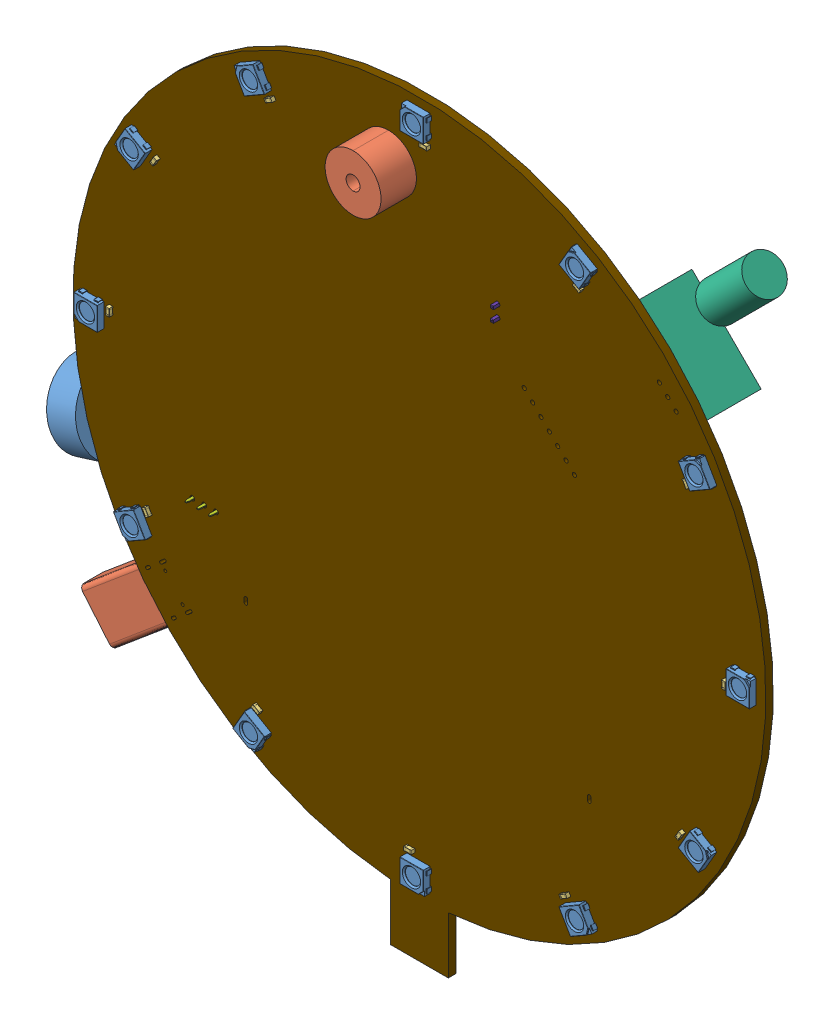
SolidWorks assembly Semafor2_kompletni, configuration Výchozí. Lengths in mm.
Overall size (154.19 160.68 28.8).
173 component instances, 20 part files, 6 mates.
Components (placement in the parent):
- Semafor2-1: Semafor2 [Výchozí] at origin size (148.79 160.68 28.8)
  - Semafor2.step-1: Semafor2.step [Výchozí] at origin size (148.79 160.68 28.8)
    - LED_WS2812B_PLCC4_5.0x5.0mm_P3.2mm.step-1: LED_WS2812B_PLCC4_5.0x5.0mm_P3.2mm.step [Výchozí] at (-39.4282 65.1 1.65) x (0.5 0.866025 0) z (0 0 1) size (5.4 5 1.6)
      - SOLID.step-1: SOLID.step [Výchozí] at origin size (5.4 5 1.6)
    - Piezo.step-1: Piezo.step [Výchozí] at (-106.6 158.895 1.65) x (1 0 0) z (0 -1 0) size (12 7.6 12)
      - SOLID-0.step-1: SOLID-0.step [Výchozí] at origin size (12 7.6 12)
    - LED_WS2812B_PLCC4_5.0x5.0mm_P3.2mm.step-2: LED_WS2812B_PLCC4_5.0x5.0mm_P3.2mm.step [Výchozí] at (-30.05 100.1 1.65) x (0 1 0) z (0 0 1) size (5.4 5 1.6)
      - SOLID.step-1: SOLID.step [Výchozí] at origin size (5.4 5 1.6)
    - LED_WS2812B_PLCC4_5.0x5.0mm_P3.2mm.step-3: LED_WS2812B_PLCC4_5.0x5.0mm_P3.2mm.step [Výchozí] at (-170.05 100.1 1.65) x (0 -1 0) z (0 0 1) size (5.4 5 1.6)
      - SOLID.step-1: SOLID.step [Výchozí] at origin size (5.4 5 1.6)
    - C_0603_1608Metric.step-1: C_0603_1608Metric.step [Výchozí] at (-101.75 33.8 1.65) size (1.6 0.8 0.8)
      - SOLID-1.step-1: SOLID-1.step [Výchozí] at origin size (1.6 0.8 0.8)
    - C_0603_1608Metric.step-2: C_0603_1608Metric.step [Výchozí] at (-43.5875 65.6288 1.65) x (0.5 0.866025 0) z (0 0 1) size (1.6 0.8 0.8)
      - SOLID-1.step-1: SOLID-1.step [Výchozí] at origin size (1.6 0.8 0.8)
    - C_0603_1608Metric.step-3: C_0603_1608Metric.step [Výchozí] at (-134.4288 43.6125 1.65) x (0.866025 -0.5 0) z (0 0 1) size (1.6 0.8 0.8)
      - SOLID-1.step-1: SOLID-1.step [Výchozí] at origin size (1.6 0.8 0.8)
    - C_0603_1608Metric.step-4: C_0603_1608Metric.step [Výchozí] at (-166.15 101.75 1.65) x (0 -1 0) z (0 0 1) size (1.6 0.8 0.8)
      - SOLID-1.step-1: SOLID-1.step [Výchozí] at origin size (1.6 0.8 0.8)
    - LED_WS2812B_PLCC4_5.0x5.0mm_P3.2mm.step-4: LED_WS2812B_PLCC4_5.0x5.0mm_P3.2mm.step [Výchozí] at (-100.05 30.1 1.65) size (5.4 5 1.6)
      - SOLID.step-1: SOLID.step [Výchozí] at origin size (5.4 5 1.6)
    - C_0603_1608Metric.step-5: C_0603_1608Metric.step [Výchozí] at (-158.05 68.5 1.65) x (0.5 -0.866025 0) z (0 0 1) size (1.6 0.8 0.8)
      - SOLID-1.step-1: SOLID-1.step [Výchozí] at origin size (1.6 0.8 0.8)
    - C_0603_1608Metric.step-6: C_0603_1608Metric.step [Výchozí] at (-68.35 41.95 1.65) x (0.866025 0.5 0) z (0 0 1) size (1.6 0.8 0.8)
      - SOLID-1.step-1: SOLID-1.step [Výchozí] at origin size (1.6 0.8 0.8)
    - LED_WS2812B_PLCC4_5.0x5.0mm_P3.2mm.step-5: LED_WS2812B_PLCC4_5.0x5.0mm_P3.2mm.step [Výchozí] at (-100.05 170.1 1.65) x (-1 0 0) z (0 0 1) size (5.4 5 1.6)
      - SOLID.step-1: SOLID.step [Výchozí] at origin size (5.4 5 1.6)
    - LED_WS2812B_PLCC4_5.0x5.0mm_P3.2mm.step-6: LED_WS2812B_PLCC4_5.0x5.0mm_P3.2mm.step [Výchozí] at (-39.4282 135.1 1.65) x (-0.5 0.866025 0) z (0 0 1) size (5.4 5 1.6)
      - SOLID.step-1: SOLID.step [Výchozí] at origin size (5.4 5 1.6)
    - LED_WS2812B_PLCC4_5.0x5.0mm_P3.2mm.step-7: LED_WS2812B_PLCC4_5.0x5.0mm_P3.2mm.step [Výchozí] at (-160.6718 65.1 1.65) x (0.5 -0.866025 0) z (0 0 1) size (5.4 5 1.6)
      - SOLID.step-1: SOLID.step [Výchozí] at origin size (5.4 5 1.6)
    - LED_WS2812B_PLCC4_5.0x5.0mm_P3.2mm.step-8: LED_WS2812B_PLCC4_5.0x5.0mm_P3.2mm.step [Výchozí] at (-65.05 39.4782 1.65) x (0.866025 0.5 0) z (0 0 1) size (5.4 5 1.6)
      - SOLID.step-1: SOLID.step [Výchozí] at origin size (5.4 5 1.6)
    - C_0603_1608Metric.step-7: C_0603_1608Metric.step [Výchozí] at (-65.45 156.55 1.65) x (-0.866025 0.5 0) z (0 0 1) size (1.6 0.8 0.8)
      - SOLID-1.step-1: SOLID-1.step [Výchozí] at origin size (1.6 0.8 0.8)
    - C_0603_1608Metric.step-8: C_0603_1608Metric.step [Výchozí] at (-33.9 98.45 1.65) x (0 1 0) z (0 0 1) size (1.6 0.8 0.8)
      - SOLID-1.step-1: SOLID-1.step [Výchozí] at origin size (1.6 0.8 0.8)
    - C_0603_1608Metric.step-9: C_0603_1608Metric.step [Výchozí] at (-98.4 166.3 1.65) x (-1 0 0) z (0 0 1) size (1.6 0.8 0.8)
      - SOLID-1.step-1: SOLID-1.step [Výchozí] at origin size (1.6 0.8 0.8)
    - LED_WS2812B_PLCC4_5.0x5.0mm_P3.2mm.step-9: LED_WS2812B_PLCC4_5.0x5.0mm_P3.2mm.step [Výchozí] at (-160.6718 135.1 1.65) x (-0.5 -0.866025 0) z (0 0 1) size (5.4 5 1.6)
      - SOLID.step-1: SOLID.step [Výchozí] at origin size (5.4 5 1.6)
    - LED_WS2812B_PLCC4_5.0x5.0mm_P3.2mm.step-10: LED_WS2812B_PLCC4_5.0x5.0mm_P3.2mm.step [Výchozí] at (-65.05 160.7218 1.65) x (-0.866025 0.5 0) z (0 0 1) size (5.4 5 1.6)
      - SOLID.step-1: SOLID.step [Výchozí] at origin size (5.4 5 1.6)
    - C_0603_1608Metric.step-10: C_0603_1608Metric.step [Výchozí] at (-156.35 134.6 1.65) x (-0.5 -0.866025 0) z (0 0 1) size (1.6 0.8 0.8)
      - SOLID-1.step-1: SOLID-1.step [Výchozí] at origin size (1.6 0.8 0.8)
    - LED_WS2812B_PLCC4_5.0x5.0mm_P3.2mm.step-11: LED_WS2812B_PLCC4_5.0x5.0mm_P3.2mm.step [Výchozí] at (-135.05 160.7218 1.65) x (-0.866025 -0.5 0) z (0 0 1) size (5.4 5 1.6)
      - SOLID.step-1: SOLID.step [Výchozí] at origin size (5.4 5 1.6)
    - C_0603_1608Metric.step-11: C_0603_1608Metric.step [Výchozí] at (-131.65 158.3 1.65) x (-0.866025 -0.5 0) z (0 0 1) size (1.6 0.8 0.8)
      - SOLID-1.step-1: SOLID-1.step [Výchozí] at origin size (1.6 0.8 0.8)
    - C_0603_1608Metric.step-12: C_0603_1608Metric.step [Výchozí] at (-42.05 131.8 1.65) x (-0.5 0.866025 0) z (0 0 1) size (1.6 0.8 0.8)
      - SOLID-1.step-1: SOLID-1.step [Výchozí] at origin size (1.6 0.8 0.8)
    - LED_WS2812B_PLCC4_5.0x5.0mm_P3.2mm.step-12: LED_WS2812B_PLCC4_5.0x5.0mm_P3.2mm.step [Výchozí] at (-135.05 39.4782 1.65) x (0.866025 -0.5 0) z (0 0 1) size (5.4 5 1.6)
      - SOLID.step-1: SOLID.step [Výchozí] at origin size (5.4 5 1.6)
    - R_0603_1608Metric.step-1: R_0603_1608Metric.step [Výchozí] at (-119.75 147.925 -0.05) x (0 -1 0) z (0 0 -1) size (1.6 0.8 0.45)
      - SOLID-2.step-1: SOLID-2.step [Výchozí] at origin size (1.6 0.8 0.45)
    - R_0603_1608Metric.step-2: R_0603_1608Metric.step [Výchozí] at (-115.95 147.9 -0.05) x (0 -1 0) z (0 0 -1) size (1.6 0.8 0.45)
      - SOLID-2.step-1: SOLID-2.step [Výchozí] at origin size (1.6 0.8 0.45)
    - D_SOD-123.step-1: D_SOD-123.step [Výchozí] at (-130.0125 82.075 -0.05) x (-1 0 0) z (0 0 -1) size (3.8 1.6 1.25)
      - SOLID-3.step-1: SOLID-3.step [Výchozí] at origin size (3.8 1.6 1.25)
    - E22_900T22D.step-1: E22_900T22D.step [Výchozí] at (-60.45 137.7711 -0.05) x (-0.707107 -0.707107 0) z (0 0 -1) size (50 21 17.3)
      - SOLID-4.step-1: SOLID-4.step [Výchozí] at origin size (50 21 17.3)
    - D_SOD-123.step-2: D_SOD-123.step [Výchozí] at (-96.1 29.05 -0.05) x (0 -1 0) z (0 0 -1) size (3.8 1.6 1.25)
      - SOLID-3.step-1: SOLID-3.step [Výchozí] at origin size (3.8 1.6 1.25)
    - PinSocket_1x03_P2.54mm_Vertical.step-1: PinSocket_1x03_P2.54mm_Vertical.step [Výchozí] at (-143.675 75.375 -0.05) x (0 1 0) z (0 0 -1) size (2.54 7.62 10.1)
      - SOLID-5.step-1: SOLID-5.step [Výchozí] at origin size (2.54 7.62 10.1)
    - D_SOD-323.step-1: D_SOD-323.step [Výchozí] at (-142.6 58.8 -0.05) x (0.642788 -0.766044 0) z (0 0 -1) size (2.5 1.25 1.1)
      - SOLID-6.step-1: SOLID-6.step [Výchozí] at origin size (2.5 1.25 1.1)
    - C_0603_1608Metric.step-13: C_0603_1608Metric.step [Výchozí] at (-158.9591 131.0993 -0.05) x (-0.939693 0.34202 0) z (0 0 -1) size (1.6 0.8 0.8)
      - SOLID-1.step-1: SOLID-1.step [Výchozí] at origin size (1.6 0.8 0.8)
    - R_0603_1608Metric.step-3: R_0603_1608Metric.step [Výchozí] at (-83.3756 132.275 -0.05) x (-1 0 0) z (0 0 -1) size (1.6 0.8 0.45)
      - SOLID-2.step-1: SOLID-2.step [Výchozí] at origin size (1.6 0.8 0.45)
    - R_0603_1608Metric.step-4: R_0603_1608Metric.step [Výchozí] at (-118.05 147.9 -0.05) x (0 -1 0) z (0 0 -1) size (1.6 0.8 0.45)
      - SOLID-2.step-1: SOLID-2.step [Výchozí] at origin size (1.6 0.8 0.45)
    - R_0603_1608Metric.step-5: R_0603_1608Metric.step [Výchozí] at (-116.95 136.3 -0.05) x (0 -1 0) z (0 0 -1) size (1.6 0.8 0.45)
      - SOLID-2.step-1: SOLID-2.step [Výchozí] at origin size (1.6 0.8 0.45)
    - C_0805_2012Metric.step-1: C_0805_2012Metric.step [Výchozí] at (-152.9591 126.5493 -0.05) x (0.939693 -0.34202 0) z (0 0 -1) size (2 1.25 1.25)
      - SOLID-7.step-1: SOLID-7.step [Výchozí] at origin size (2 1.25 1.25)
    - LED_0603_1608Metric.step-1: LED_0603_1608Metric.step [Výchozí] at (-147.525 84.025 -0.05) x (-1 0 0) z (0 0 -1) size (1.6 0.8 1.1)
      - SOLID-8.step-1: SOLID-8.step [Výchozí] at origin size (1.6 0.8 1.1)
    - SOT-23.step-1: SOT-23.step [Výchozí] at (-83.3256 136.55 -0.05) x (0 1 0) z (0 0 -1) size (2.5 3 1.2)
      - SOLID-9.step-1: SOLID-9.step [Výchozí] at origin size (2.5 3 1.2)
    - SOT-23.step-2: SOT-23.step [Výchozí] at (-146.9091 122.0993 -0.05) x (0.939693 -0.34202 0) z (0 0 -1) size (2.5 3 1.2)
      - SOLID-9.step-1: SOLID-9.step [Výchozí] at origin size (2.5 3 1.2)
    - R_0603_1608Metric.step-6: R_0603_1608Metric.step [Výchozí] at (-120.725 43.975 -0.05) x (-1 0 0) z (0 0 -1) size (1.6 0.8 0.45)
      - SOLID-2.step-1: SOLID-2.step [Výchozí] at origin size (1.6 0.8 0.45)
    - C_0805_2012Metric.step-2: C_0805_2012Metric.step [Výchozí] at (-159.7591 129.0993 -0.05) x (-0.939693 0.34202 0) z (0 0 -1) size (2 1.25 1.25)
      - SOLID-7.step-1: SOLID-7.step [Výchozí] at origin size (2 1.25 1.25)
    - R_0603_1608Metric.step-7: R_0603_1608Metric.step [Výchozí] at (-120.15 136.3 -0.05) x (0 -1 0) z (0 0 -1) size (1.6 0.8 0.45)
      - SOLID-2.step-1: SOLID-2.step [Výchozí] at origin size (1.6 0.8 0.45)
    - D_SOD-323.step-2: D_SOD-323.step [Výchozí] at (-147.5 62.875 -0.05) x (-0.766044 -0.642788 0) z (0 0 -1) size (2.5 1.25 1.1)
      - SOLID-6.step-1: SOLID-6.step [Výchozí] at origin size (2.5 1.25 1.1)
    - C_0805_2012Metric.step-3: C_0805_2012Metric.step [Výchozí] at (-128.3875 78.75 -0.05) x (0 -1 0) z (0 0 -1) size (2 1.25 1.25)
      - SOLID-7.step-1: SOLID-7.step [Výchozí] at origin size (2 1.25 1.25)
    - R_0603_1608Metric.step-8: R_0603_1608Metric.step [Výchozí] at (-143.0091 117.4493 -0.05) x (0.939693 -0.34202 0) z (0 0 -1) size (1.6 0.8 0.45)
      - SOLID-2.step-1: SOLID-2.step [Výchozí] at origin size (1.6 0.8 0.45)
    - LED_0603_1608Metric.step-2: LED_0603_1608Metric.step [Výchozí] at (-109.425 43.2125 -0.05) x (0 -1 0) z (0 0 -1) size (1.6 0.8 1.1)
      - SOLID-8.step-1: SOLID-8.step [Výchozí] at origin size (1.6 0.8 1.1)
    - R_0603_1608Metric.step-9: R_0603_1608Metric.step [Výchozí] at (-135.1875 77.025 -0.05) x (0 1 0) z (0 0 -1) size (1.6 0.8 0.45)
      - SOLID-2.step-1: SOLID-2.step [Výchozí] at origin size (1.6 0.8 0.45)
    - USB_C.step-1: USB_C.step [Výchozí] at (-154.7 55.1 -0.05) x (-0.766044 -0.642788 0) z (0 0 -1) size (7.5 9 3.5)
      - SOLID-10.step-1: SOLID-10.step [Výchozí] at origin size (7.5 9 3.5)
    - Battery_pack.step-1: Battery_pack.step [Výchozí] at (-99.9 62.1 -0.05) x (-1 0 0) z (0 0 -1) size (77 21 19.5)
      - SOLID-11.step-1: SOLID-11.step [Výchozí] at origin size (77 21 19.5)
    - LED_0603_1608Metric.step-3: LED_0603_1608Metric.step [Výchozí] at (-107.575 43.225 -0.05) x (0 -1 0) z (0 0 -1) size (1.6 0.8 1.1)
      - SOLID-8.step-1: SOLID-8.step [Výchozí] at origin size (1.6 0.8 1.1)
    - R_0603_1608Metric.step-10: R_0603_1608Metric.step [Výchozí] at (-144.1125 87.05 -0.05) x (1 0 0) z (0 0 -1) size (1.6 0.8 0.45)
      - SOLID-2.step-1: SOLID-2.step [Výchozí] at origin size (1.6 0.8 0.45)
    - D_SOD-123.step-3: D_SOD-123.step [Výchozí] at (-117.975 155.17 -0.05) x (-1 0 0) z (0 0 -1) size (3.8 1.6 1.25)
      - SOLID-3.step-1: SOLID-3.step [Výchozí] at origin size (3.8 1.6 1.25)
    - R_0603_1608Metric.step-11: R_0603_1608Metric.step [Výchozí] at (-114.175 160.345 -0.05) x (0 -1 0) z (0 0 -1) size (1.6 0.8 0.45)
      - SOLID-2.step-1: SOLID-2.step [Výchozí] at origin size (1.6 0.8 0.45)
    - R_0603_1608Metric.step-12: R_0603_1608Metric.step [Výchozí] at (-150.9091 118.3743 -0.05) x (-0.34202 -0.939693 0) z (0 0 -1) size (1.6 0.8 0.45)
      - SOLID-2.step-1: SOLID-2.step [Výchozí] at origin size (1.6 0.8 0.45)
    - D_SOD-323.step-3: D_SOD-323.step [Výchozí] at (-98.4 29.65 -0.05) x (0 1 0) z (0 0 -1) size (2.5 1.25 1.1)
      - SOLID-6.step-1: SOLID-6.step [Výchozí] at origin size (2.5 1.25 1.1)
    - SOIC-14_3.9x8.7mm_P1.27mm.step-1: SOIC-14_3.9x8.7mm_P1.27mm.step [Výchozí] at (-118.5 142.1 -0.05) x (0 -1 0) z (0 0 -1) size (6 8.7 1.75)
      - SOLID-12.step-1: SOLID-12.step [Výchozí] at origin size (6 8.7 1.75)
    - C_0603_1608Metric.step-14: C_0603_1608Metric.step [Výchozí] at (-124.55 142.3493 -0.05) x (0 -1 0) z (0 0 -1) size (1.6 0.8 0.8)
      - SOLID-1.step-1: SOLID-1.step [Výchozí] at origin size (1.6 0.8 0.8)
    - R_0603_1608Metric.step-13: R_0603_1608Metric.step [Výchozí] at (-147.4841 125.4493 -0.05) x (0.939693 -0.34202 0) z (0 0 -1) size (1.6 0.8 0.45)
      - SOLID-2.step-1: SOLID-2.step [Výchozí] at origin size (1.6 0.8 0.45)
    - C_0805_2012Metric.step-4: C_0805_2012Metric.step [Výchozí] at (-126.5 142.3993 -0.05) x (0 -1 0) z (0 0 -1) size (2 1.25 1.25)
      - SOLID-7.step-1: SOLID-7.step [Výchozí] at origin size (2 1.25 1.25)
    - R_0603_1608Metric.step-14: R_0603_1608Metric.step [Výchozí] at (-139.1625 81.2 -0.05) x (0 -1 0) z (0 0 -1) size (1.6 0.8 0.45)
      - SOLID-2.step-1: SOLID-2.step [Výchozí] at origin size (1.6 0.8 0.45)
    - R_0603_1608Metric.step-15: R_0603_1608Metric.step [Výchozí] at (-132.6875 77.875 -0.05) x (1 0 0) z (0 0 -1) size (1.6 0.8 0.45)
      - SOLID-2.step-1: SOLID-2.step [Výchozí] at origin size (1.6 0.8 0.45)
    - SOT-23.step-3: SOT-23.step [Výchozí] at (-118.675 160.445 -0.05) x (-1 0 0) z (0 0 -1) size (2.5 3 1.2)
      - SOLID-9.step-1: SOLID-9.step [Výchozí] at origin size (2.5 3 1.2)
    - R_0402_1005Metric.step-1: R_0402_1005Metric.step [Výchozí] at (-150.45 61 -0.05) x (0.766044 0.642788 0) z (0 0 -1) size (1 0.5 0.35)
      - SOLID-13.step-1: SOLID-13.step [Výchozí] at origin size (1 0.5 0.35)
    - C_0805_2012Metric.step-5: C_0805_2012Metric.step [Výchozí] at (-114.675 48.525 -0.05) x (-1 0 0) z (0 0 -1) size (2 1.25 1.25)
      - SOLID-7.step-1: SOLID-7.step [Výchozí] at origin size (2 1.25 1.25)
    - R_0603_1608Metric.step-16: R_0603_1608Metric.step [Výchozí] at (-152.1341 114.7493 -0.05) x (-0.34202 -0.939693 0) z (0 0 -1) size (1.6 0.8 0.45)
      - SOLID-2.step-1: SOLID-2.step [Výchozí] at origin size (1.6 0.8 0.45)
    - C_0603_1608Metric.step-15: C_0603_1608Metric.step [Výchozí] at (-78.4756 143.175 -0.05) x (0 -1 0) z (0 0 -1) size (1.6 0.8 0.8)
      - SOLID-1.step-1: SOLID-1.step [Výchozí] at origin size (1.6 0.8 0.8)
    - C_0805_2012Metric.step-6: C_0805_2012Metric.step [Výchozí] at (-120.625 46.525 -0.05) x (-1 0 0) z (0 0 -1) size (2 1.25 1.25)
      - SOLID-7.step-1: SOLID-7.step [Výchozí] at origin size (2 1.25 1.25)
    - R_0603_1608Metric.step-17: R_0603_1608Metric.step [Výchozí] at (-115.3 136.3 -0.05) x (0 1 0) z (0 0 -1) size (1.6 0.8 0.45)
      - SOLID-2.step-1: SOLID-2.step [Výchozí] at origin size (1.6 0.8 0.45)
    - SOT-23-5.step-1: SOT-23-5.step [Výchozí] at (-135.2875 81.1 -0.05) x (-1 0 0) z (0 0 -1) size (2.8 2.9 1.55)
      - SOLID-14.step-1: SOLID-14.step [Výchozí] at origin size (2.8 2.9 1.55)
    - R_0402_1005Metric.step-2: R_0402_1005Metric.step [Výchozí] at (-148.35 58.75 -0.05) x (0.766044 0.642788 0) z (0 0 -1) size (1 0.5 0.35)
      - SOLID-13.step-1: SOLID-13.step [Výchozí] at origin size (1 0.5 0.35)
    - C_0805_2012Metric.step-7: C_0805_2012Metric.step [Výchozí] at (-136.7875 84.075 -0.05) x (1 0 0) z (0 0 -1) size (2 1.25 1.25)
      - SOLID-7.step-1: SOLID-7.step [Výchozí] at origin size (2 1.25 1.25)
    - PinHeader_1x02_P2.54mm_Vertical.step-1: PinHeader_1x02_P2.54mm_Vertical.step [Výchozí] at (-83.2244 144.25 -0.05) x (-1 0 0) z (0 0 -1) size (2.54 5.08 11.54)
      - SOLID-15.step-1: SOLID-15.step [Výchozí] at origin size (2.54 5.08 11.54)
    - D_SOD-323.step-4: D_SOD-323.step [Výchozí] at (-146.2 61.275 -0.05) x (-0.766044 -0.642788 0) z (0 0 -1) size (2.5 1.25 1.1)
      - SOLID-6.step-1: SOLID-6.step [Výchozí] at origin size (2.5 1.25 1.1)
    - LED_0603_1608Metric.step-4: LED_0603_1608Metric.step [Výchozí] at (-147.5125 87.075 -0.05) x (-1 0 0) z (0 0 -1) size (1.6 0.8 1.1)
      - SOLID-8.step-1: SOLID-8.step [Výchozí] at origin size (1.6 0.8 1.1)
    - R_0603_1608Metric.step-18: R_0603_1608Metric.step [Výchozí] at (-156.1591 128.8493 -0.05) x (0.939693 -0.34202 0) z (0 0 -1) size (1.6 0.8 0.45)
      - SOLID-2.step-1: SOLID-2.step [Výchozí] at origin size (1.6 0.8 0.45)
    - R_0603_1608Metric.step-19: R_0603_1608Metric.step [Výchozí] at (-144.15 84.05 -0.05) x (1 0 0) z (0 0 -1) size (1.6 0.8 0.45)
      - SOLID-2.step-1: SOLID-2.step [Výchozí] at origin size (1.6 0.8 0.45)
    - R_0603_1608Metric.step-20: R_0603_1608Metric.step [Výchozí] at (-110.275 40.775 -0.05) x (1 0 0) z (0 0 -1) size (1.6 0.8 0.45)
      - SOLID-2.step-1: SOLID-2.step [Výchozí] at origin size (1.6 0.8 0.45)
    - D_SOD-123.step-4: D_SOD-123.step [Výchozí] at (-144.6 55.65 -0.05) x (-0.766044 -0.642788 0) z (0 0 -1) size (3.8 1.6 1.25)
      - SOLID-3.step-1: SOLID-3.step [Výchozí] at origin size (3.8 1.6 1.25)
    - SOT-23.step-4: SOT-23.step [Výchozí] at (-143.8591 114.7993 -0.05) x (0.939693 -0.34202 0) z (0 0 -1) size (2.5 3 1.2)
      - SOLID-9.step-1: SOLID-9.step [Výchozí] at origin size (2.5 3 1.2)
    - R_0603_1608Metric.step-21: R_0603_1608Metric.step [Výchozí] at (-155.1091 131.9243 -0.05) x (-0.34202 -0.939693 0) z (0 0 -1) size (1.6 0.8 0.45)
      - SOLID-2.step-1: SOLID-2.step [Výchozí] at origin size (1.6 0.8 0.45)
    - R_0603_1608Metric.step-22: R_0603_1608Metric.step [Výchozí] at (-118.55 136.3 -0.05) x (0 -1 0) z (0 0 -1) size (1.6 0.8 0.45)
      - SOLID-2.step-1: SOLID-2.step [Výchozí] at origin size (1.6 0.8 0.45)
    - R_0603_1608Metric.step-23: R_0603_1608Metric.step [Výchozí] at (-121.75 136.2993 -0.05) x (0 -1 0) z (0 0 -1) size (1.6 0.8 0.45)
      - SOLID-2.step-1: SOLID-2.step [Výchozí] at origin size (1.6 0.8 0.45)
    - D_SOD-123.step-5: D_SOD-123.step [Výchozí] at (-74.5506 143.175 -0.05) x (0 -1 0) z (0 0 -1) size (3.8 1.6 1.25)
      - SOLID-3.step-1: SOLID-3.step [Výchozí] at origin size (3.8 1.6 1.25)
    - Semafor PCB.step-1: Semafor PCB.step [Výchozí] at origin size (148.79 160.68 1.6)
- Button-2: Button [Výchozí] at (-163.9042 80.1546 -4.5) x (-0.296139 0.955145 0) z (0 0 1) size (17 22 17)
- USB_cable-1: USB_cable [Výchozí] at (-163.701 47.5472 -4.8) x (0.766044 0.642788 0) z (0 0 1) size (20 11 6)
Mates (geometry in assembly coordinates):
- Tečná1: tangent: plane of assembly; face of Semafor2-1/Semafor2.step-1/USB_C.step-1/SOLID-10.step-1; plane of USB_cable-1 through (-156.7582 57.9419 -2.55) normal (0 0 -1)
- Tečná2: tangent: plane of assembly; face of Semafor2-1/Semafor2.step-1/USB_C.step-1/SOLID-10.step-1; plane of USB_cable-1 through (-156.7582 57.9419 -1.05) normal (-0.642788 0.766044 0)
- Tečná3: tangent: plane of assembly; face of Semafor2-1/Semafor2.step-1/USB_C.step-1/SOLID-10.step-1; plane of USB_cable-1 through (-161.108 56.9028 1.2) normal (0.766044 0.642788 0)
- Sjednocená1: coincident anti-aligned: plane of Semafor2-1/Semafor2.step-1/Semafor PCB.step-1 through (-100.0019 93.8452 0) normal (0 0 -1); plane of Button-2 through (-169.217 71.9639 0) normal (0 0 1)
- Tečná4: tangent anti-aligned: cylinder of Semafor2-1/Semafor2.step-1/Semafor PCB.step-1 through (-100 99.9315 0) axis (0 0 -1) radius 74.3945; plane of Button-2
- Zámek1: lock: unknown of Semafor2-1/Semafor2.step-1/USB_C.step-1/SOLID-10.step-1; unknown of Button-2
